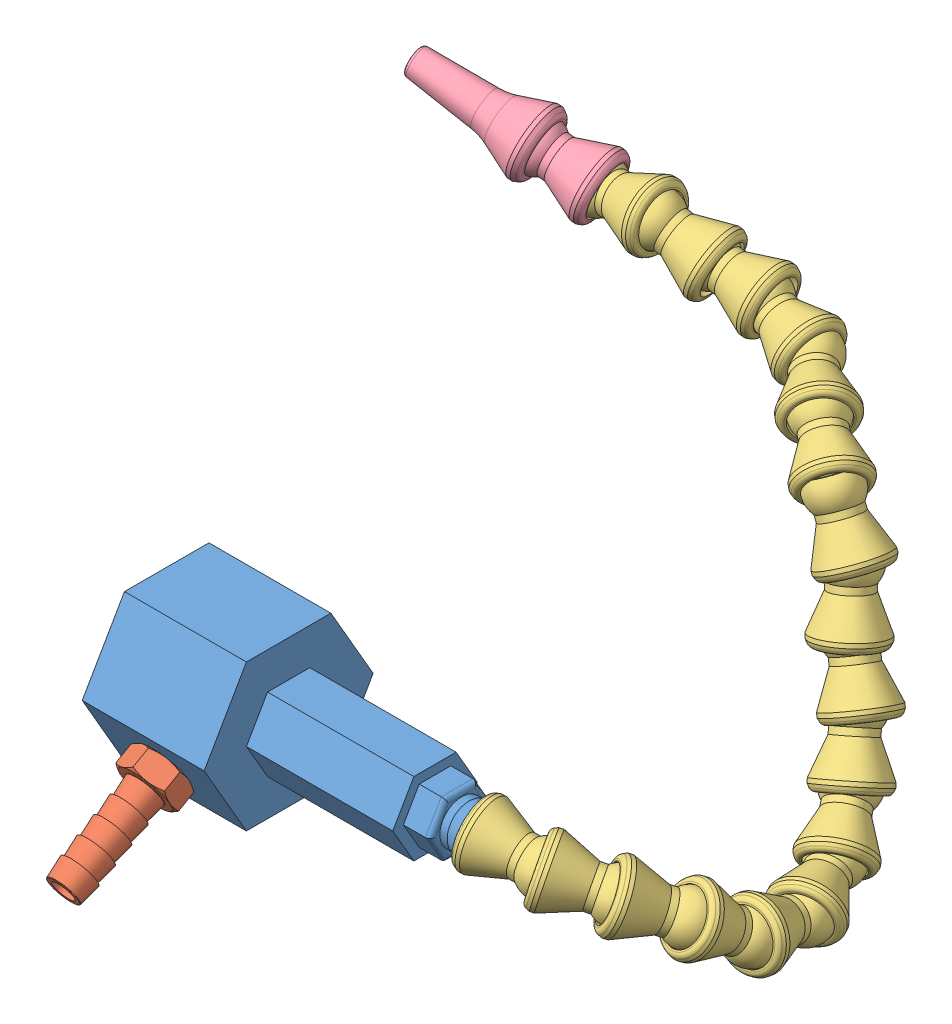
SolidWorks assembly Coolant Nozzle, configuration Default. Lengths in mm.
Overall size (166.4 115.86 164.55).
20 component instances, 4 part files, 37 mates.
Components (placement in the parent):
- Nozzle Fitting-2: Nozzle Fitting [10095K11] x (-1 0 0) z (0 0 -1) size (85.5 38.1 43.99)
- Coolant Hose Fitting-1: Coolant Hose Fitting [5346K15] at (-218.9607 -12.3825 21.4471) x (-0.5 -0.75 -0.433013) z (0 -0.5 0.866025) size (12.7 14.66 40.16)
- Nozzle Segment-1: Nozzle Segment [10095K11] at (-145.0876 -1.1724 -1.3265) x (-0.964781 0.174204 0.197107) z (0.236277 0.244493 0.940424) size (19.23 16.38 16.38)
- Nozzle Segment-2: Nozzle Segment [10095K11] at (-132.1876 -4.3233 -6.4261) x (-0.812639 0.264519 0.519277) z (-0.559714 -0.602411 -0.569053) size (19.23 16.38 16.38)
- Nozzle Segment-3: Nozzle Segment [10095K11] at (-121.833 -8.4976 -14.4255) x (-0.636222 0.365674 0.679341) z (-0.74211 -0.049315 -0.668461) size (19.23 16.38 16.38)
- Nozzle Segment-4: Nozzle Segment [10095K11] at (-115.3648 -15.2282 -25.561) x (-0.251037 0.530272 0.80981) z (0.716586 -0.460628 0.523762) size (19.23 16.38 16.38)
- Nozzle Segment-5: Nozzle Segment [10095K11] at (-114.122 -20.5544 -39.2225) x (0.060142 0.200852 0.977774) z (0.850132 0.503047 -0.155625) size (19.23 16.38 16.38)
- Nozzle Segment-6: Nozzle Segment [10095K11] at (-117.7258 -20.2982 -53.6) x (0.376661 -0.192635 0.906101) z (0.80261 -0.420536 -0.423045) size (19.23 16.38 16.38)
- Nozzle Segment-7: Nozzle Segment [10095K11] at (-123.8281 -14.7369 -65.448) x (0.447959 -0.551051 0.704042) z (-0.57786 -0.779335 -0.242309) size (19.23 16.38 16.38)
- Nozzle Segment-8: Nozzle Segment [10095K11] at (-129.6583 -4.5901 -73.7852) x (0.34786 -0.830559 0.434931) z (-0.208068 -0.520725 -0.827981) size (19.23 16.38 16.38)
- Nozzle Segment-9: Nozzle Segment [10095K11] at (-134.5787 6.5762 -79.2387) x (0.450404 -0.845417 0.287064) z (-0.124498 0.258912 0.957844) size (19.23 16.38 16.38)
- Nozzle Segment-10: Nozzle Segment [10095K11] at (-139.9193 18.37 -83.1837) x (0.248587 -0.921745 0.297641) z (-0.078679 0.287056 0.954677) size (19.23 16.38 16.38)
- Nozzle Segment-11: Nozzle Segment [10095K11] at (-145.0004 31.0108 -86.3373) x (0.502102 -0.855633 0.125643) z (0.304823 0.311061 0.90018) size (19.23 16.38 16.38)
- Nozzle Segment-12: Nozzle Segment [10095K11] at (-155.1715 40.8641 -91.8827) x (0.736505 -0.445413 0.509084) z (-0.496881 -0.866913 -0.039639) size (19.23 16.38 16.38)
- Nozzle Segment-13: Nozzle Segment [10095K11] at (-165.339 46.0134 -99.382) x (0.748506 -0.234086 0.620437) z (0.604966 0.624225 -0.494327) size (19.23 16.38 16.38)
- Nozzle Segment-14: Nozzle Segment [10095K11] at (-178.8119 49.8319 -104.6399) x (0.959495 -0.254927 0.119923) z (-0.092513 0.116959 0.988818) size (19.23 16.38 16.38)
- Nozzle Segment-15: Nozzle Segment [10095K11] at (-191.9355 53.2164 -105.3547) x (0.96721 -0.232254 -0.102779) z (-0.008651 -0.434569 0.900597) size (19.23 16.38 16.38)
- Nozzle Segment-16: Nozzle Segment [10095K11] at (-204.6409 56.1812 -104.0465) x (0.926731 -0.341594 -0.156472) z (-0.060995 -0.547706 0.834445) size (19.23 16.38 16.38)
- Nozzle Segment-17: Nozzle Segment [10095K11] at (-218.4733 58.8945 -102.6316) x (0.999297 -0.017332 -0.033247) z (-0.011366 -0.985053 0.171876) size (19.23 16.38 16.38)
- Nozzle Tip-1: Nozzle Tip [10095K11] at (-98.7192 18.7096 -128.7783) x (0.935479 -0.295623 -0.193613) z (-0.049416 -0.651936 0.756662) size (44.41 16.54 16.54)
Mates (geometry in assembly coordinates):
- ProfileCenter1: profile center anti-aligned: plane of Nozzle Fitting-2 through (-234.8357 -19.05 10.9985) normal (0 -0.5 0.866025); circle of 5346K15_Brass Barbed Hose Fitting for Air and Water-1
- Tangent2: tangent: circle of Nozzle Fitting-2; circle of Nozzle Segment-1
- Lock1: lock: unknown of Nozzle Fitting-2; unknown of Nozzle Segment-1
- Tangent3: tangent: circle of Nozzle Segment-2; circle of Nozzle Segment-1
- Lock2: lock: unknown of Nozzle Segment-1; unknown of Nozzle Segment-2
- Tangent4: tangent: circle of Nozzle Segment-2; circle of Nozzle Segment-3
- Lock3: lock: unknown of Nozzle Segment-2; unknown of Nozzle Segment-3
- Tangent5: tangent: circle of Nozzle Segment-3; circle of Nozzle Segment-4
- Lock4: lock: unknown of Nozzle Segment-3; unknown of Nozzle Segment-4
- Tangent6: tangent: circle of Nozzle Segment-4; circle of Nozzle Segment-5
- Lock5: lock: unknown of Nozzle Segment-4; unknown of Nozzle Segment-5
- Tangent7: tangent: circle of Nozzle Segment-5; circle of Nozzle Segment-6
- Lock6: lock: unknown of Nozzle Segment-5; unknown of Nozzle Segment-6
- Tangent8: tangent: circle of Nozzle Segment-6; circle of Nozzle Segment-7
- Lock7: lock: unknown of Nozzle Segment-6; unknown of Nozzle Segment-7
- Tangent9: tangent: circle of Nozzle Segment-7; circle of Nozzle Segment-8
- Lock8: lock: unknown of Nozzle Segment-7; unknown of Nozzle Segment-8
- Tangent10: tangent: circle of Nozzle Segment-8; circle of Nozzle Segment-9
- Lock9: lock: unknown of Nozzle Segment-8; unknown of Nozzle Segment-9
- Tangent11: tangent: circle of Nozzle Segment-9; circle of Nozzle Segment-10
- Lock10: lock: unknown of Nozzle Segment-9; unknown of Nozzle Segment-10
- Tangent12: tangent: circle of Nozzle Segment-10; circle of Nozzle Segment-11
- Lock11: lock: unknown of Nozzle Segment-10; unknown of Nozzle Segment-11
- Tangent13: tangent: circle of Nozzle Segment-11; circle of Nozzle Segment-12
- Lock12: lock: unknown of Nozzle Segment-11; unknown of Nozzle Segment-12
- Tangent14: tangent: circle of Nozzle Segment-12; circle of Nozzle Segment-13
- Lock13: lock: unknown of Nozzle Segment-12; unknown of Nozzle Segment-13
- Tangent15: tangent: circle of Nozzle Segment-13; circle of Nozzle Segment-14
- Lock14: lock: unknown of Nozzle Segment-13; unknown of Nozzle Segment-14
- Tangent16: tangent: circle of Nozzle Segment-14; circle of Nozzle Segment-15
- Lock15: lock: unknown of Nozzle Segment-14; unknown of Nozzle Segment-15
- Tangent17: tangent: circle of Nozzle Segment-15; circle of Nozzle Segment-16
- Lock16: lock: unknown of Nozzle Segment-15; unknown of Nozzle Segment-16
- Tangent18: tangent: circle of Nozzle Segment-16; circle of Nozzle Segment-17
- Lock17: lock: unknown of Nozzle Segment-16; unknown of Nozzle Segment-17
- Tangent20: tangent: circle of Nozzle Tip-1; circle of Nozzle Segment-17
- Lock18: lock: unknown of Nozzle Tip-1; unknown of Nozzle Segment-17
